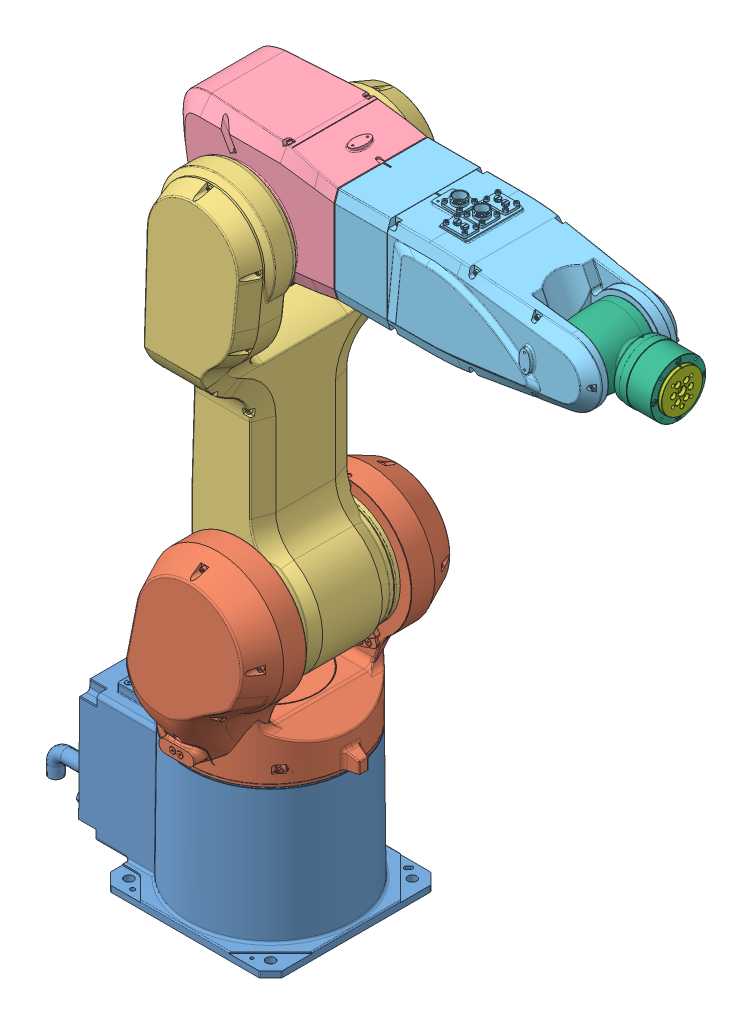
SolidWorks assembly P7B-900简化模型(可拖拽), configuration 默认. Lengths in mm.
Overall size (824 931.75 324.15).
7 component instances, 7 part files, 18 mates.
Components (placement in the parent):
- GBT-P7B-base-2: GBT-P7B-base [默认] at origin size (387 201.5 230.18)
- GBT-P7B-shoulder-2: GBT-P7B-shoulder [默认] at (0 194 0) size (233 264.18 324.15)
- GBT-P7B-900-large_arm-2: GBT-P7B-900-large_arm [默认] at (30 365 0) size (160.62 607.5 271.5)
- GBT-P7B-elbow-2: GBT-P7B-elbow [默认] at (30 815 0) size (223.57 189.32 158.51)
- GBT-P7B-900-little_arm-2: GBT-P7B-900-little_arm [默认] at (221.5 850 0) size (347 143.71 150.77)
- GBT-P7B-wrist-2: GBT-P7B-wrist [默认] at (450 850 0) size (140.37 85 79.5)
- GBT-P7B-flange-2: GBT-P7B-flange [默认] at (539 850 0) x (1 0 0) z (0 -1 0) size (18 55 55)
Mates (geometry in assembly coordinates):
- 同心1: concentric anti-aligned: cylinder of GBT-P7B-base-1-2 through (0 405.8183 0) axis (0 -1 0) radius 71; cylinder of GBT-P7B-shoulder-2 through (0 194 0) axis (0 1 0) radius 108
- 重合1: coincident anti-aligned: plane of GBT-P7B-base-1-2 through (0 190 0) normal (0 1 0); plane of GBT-P7B-shoulder-2 through (0 190 0) normal (0 -1 0)
- 重合2: coincident aligned: plane of GBT-P7B-base-2 through (0 0 0) normal (0 0 1); plane of GBT-P7B-shoulder-2 through (0 194 0) normal (0 0 1)
- 同心2: concentric aligned: cylinder of GBT-P7B-large_arm-2 through (30 365 -294.8036) axis (0 0 1) radius 74; cylinder of GBT-P7B-shoulder-2 through (30 365 -80) axis (0 0 1) radius 74
- 重合3: coincident aligned: plane of GBT-P7B-shoulder-2 through (0 194 0) normal (0 0 1); plane of GBT-P7B-large_arm-2 through (30 365 0) normal (0 0 1)
- 平行1: parallel aligned: plane of GBT-P7B-shoulder-2 through (0 194 0) normal (1 0 0); plane of GBT-P7B-large_arm-2 through (30 365 0) normal (1 0 0)
- 同心3: concentric anti-aligned: cylinder of GBT-P7B-large_arm-2 through (30 815 -85.5) axis (0 0 1) radius 57.5; cylinder of GBT-P7B-elbow-2 through (30 815 -67) axis (0 0 -1) radius 57.5
- 重合4: coincident aligned: plane of GBT-P7B-large_arm-2 through (30 365 0) normal (0 0 1); plane of GBT-P7B-elbow-2 through (30 815 0) normal (0 0 1)
- 平行2: parallel aligned: plane of GBT-P7B-large_arm-2 through (30 365 0) normal (1 0 0); plane of GBT-P7B-elbow-2 through (30 815 0) normal (1 0 0)
- 同心4: concentric aligned: cylinder of GBT-P7B-elbow-2 through (137.5 850 0) axis (-1 0 0) radius 49.5; cylinder of GBT-P7B-little_arm-2 through (153.5 850 0) axis (-1 0 0) radius 49.5
- 重合5: coincident anti-aligned: plane of GBT-P7B-elbow-2 through (153.5 850 0) normal (1 0 0); plane of GBT-P7B-little_arm-2 through (153.5 850 0) normal (-1 0 0)
- 重合6: coincident aligned: plane of GBT-P7B-elbow-2 through (30 815 0) normal (0 0 1); plane of GBT-P7B-little_arm-2 through (221.5 850 0) normal (0 0 1)
- 同心5: concentric anti-aligned: cylinder of GBT-P7B-little_arm-2 through (450 850 -74.7776) axis (0 0 -1) radius 29.5; cylinder of GBT-P7B-wrist-2 through (450 850 -27.1377) axis (0 0 1) radius 29.5
- 重合7: coincident aligned: plane of GBT-P7B-little_arm-2 through (221.5 850 0) normal (0 0 1); plane of GBT-P7B-wrist-2 through (450 850 0) normal (0 0 1)
- 平行3: parallel aligned: plane of GBT-P7B-little_arm-2 through (221.5 850 0) normal (0 1 0); plane of GBT-P7B-wrist-2 through (450 850 0) normal (0 1 0)
- 同心6: concentric anti-aligned: cylinder of GBT-P7B-wrist-2 through (539 850 0) axis (1 0 0) radius 21; cylinder of GBT-P7B-flange-2 through (539 850 0) axis (-1 0 0) radius 21
- 重合8: coincident anti-aligned: plane of GBT-P7B-wrist-2 through (539 850 -13.8) normal (1 0 0); plane of GBT-P7B-flange-2 through (539 850 5.5) normal (-1 0 0)
- 重合9: coincident aligned: plane of GBT-P7B-wrist-2 through (450 850 0) normal (0 0 1); plane of GBT-P7B-flange-2 through (539 850 0) normal (0 0 1)
